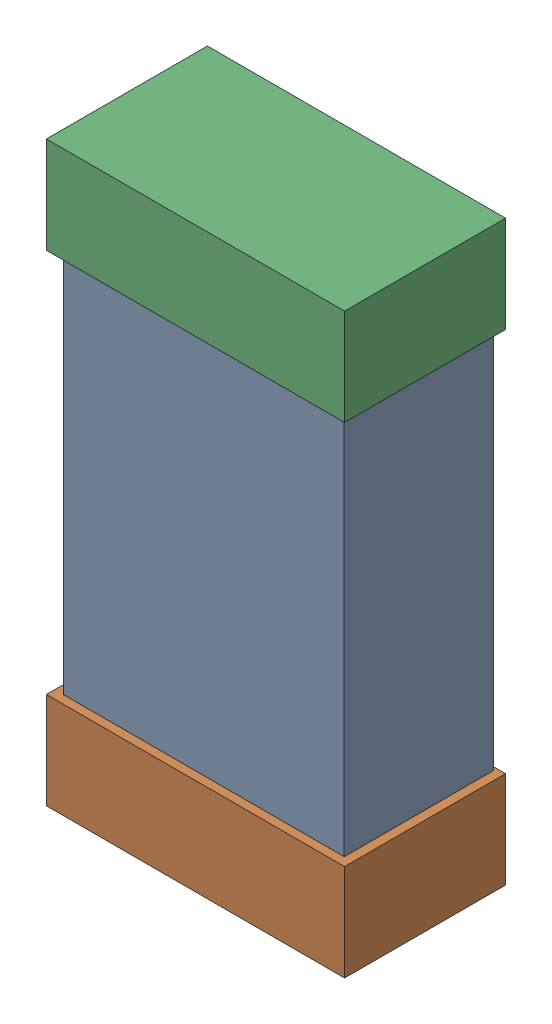
SolidWorks assembly C14, configuration Default. Lengths in mm.
Overall size (0.85 1.65 0.46).
6 component instances, 2 part files, 0 mates.
Components (placement in the parent):
- 432124816_31-1: 432124816_31 [Default] at (36.5501 24.9001 -0.8615) size (0.8 1.5 0.42)
  - Extruded (1)-1: Extruded (1) [Default] at origin size (0.8 1.5 0.42)
- 432138512_62-1: 432138512_62 [Default] at (36.5501 24.2143 -0.8715) size (0.85 0.28 0.46)
  - Extruded-1: Extruded [Default] at origin size (0.85 0.28 0.46)
- 432138512_63-1: 432138512_63 [Default] at (36.5501 25.5859 -0.8715) size (0.85 0.28 0.46)
  - Extruded-1: Extruded [Default] at origin size (0.85 0.28 0.46)
